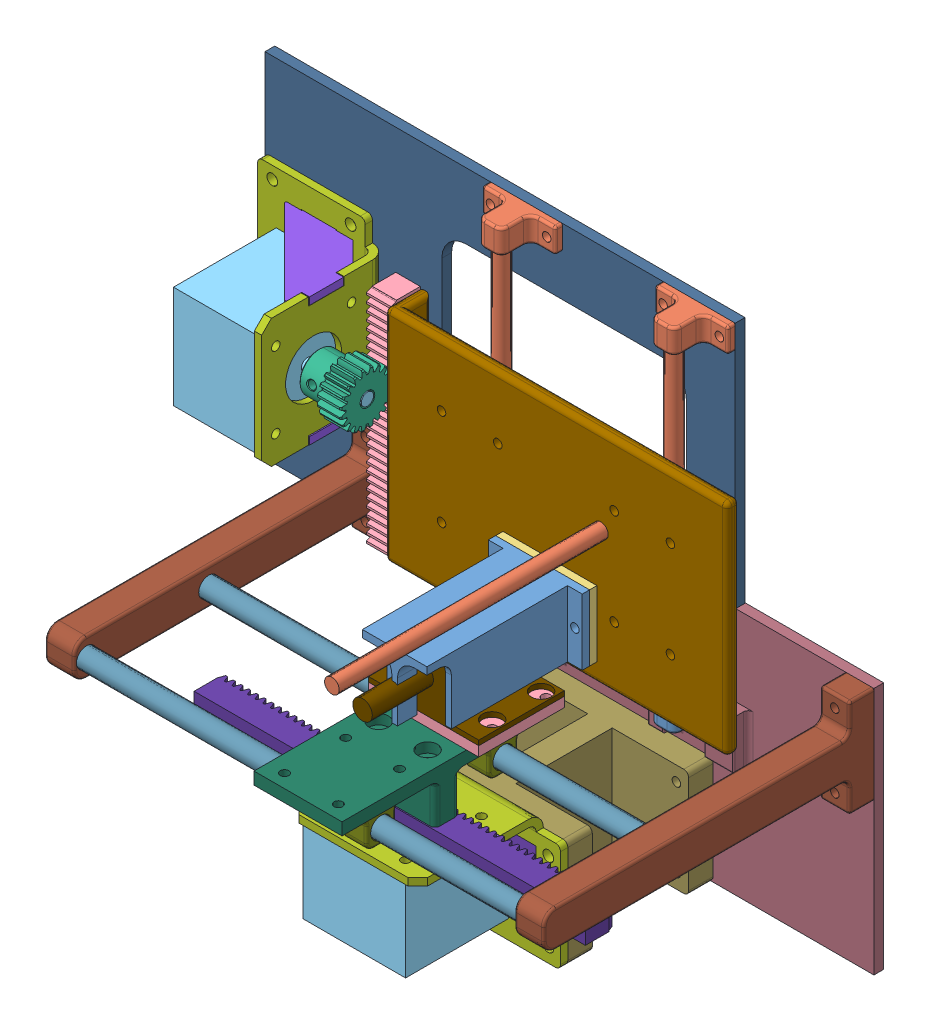
SolidWorks assembly AssemXY, configuration ﾃﾞﾌｫﾙﾄ. Lengths in mm.
Overall size (249 202.5 162.02).
43 component instances, 22 part files, 70 mates.
Components (placement in the parent):
- rinia_rail-2: rinia_rail [ﾃﾞﾌｫﾙﾄ] at (-40.4159 -125.5736 144.0481) x (1 0 0) z (0 1 0) size (30 15 144)
  - shaftholder-1: shaftholder [ﾃﾞﾌｫﾙﾄ] at (-9.9946 -2.4519 30) size (30 15 10)
  - shaft_6_4-1: shaft_6_4 [ﾃﾞﾌｫﾙﾄ] at (-9.9946 -2.4519 40) size (30 15 139)
- rinia_rail-3: rinia_rail [ﾃﾞﾌｫﾙﾄ] at (30.1841 -125.5736 144.0481) x (1 0 0) z (0 1 0) size (30 15 144)
  - shaftholder-1: shaftholder [ﾃﾞﾌｫﾙﾄ] at (-9.9946 -2.4519 30) size (30 15 10)
  - shaft_6_4-1: shaft_6_4 [ﾃﾞﾌｫﾙﾄ] at (-9.9946 -2.4519 40) size (30 15 139)
- bush_6-1: bush_6 [ﾃﾞﾌｫﾙﾄ] at (-50.4105 -14.7713 146.5) x (1 0 0) z (0 -1 0) size (30 15 10)
- bush_6-2: bush_6 [ﾃﾞﾌｫﾙﾄ] at (20.1895 -54.1713 146.5) x (1 0 0) z (0 -1 0) size (30 15 10)
- bush_6-3: bush_6 [ﾃﾞﾌｫﾙﾄ] at (-50.4105 -54.1713 146.5) x (1 0 0) z (0 -1 0) size (30 15 10)
- bush_6-4: bush_6 [ﾃﾞﾌｫﾙﾄ] at (20.1895 -14.7713 146.5) x (1 0 0) z (0 -1 0) size (30 15 10)
- RGEABL1_0Z_90_A15_B20_C20_D20-1: RGEABL1_0Z_90_A15_B20_C20_D20 [Default] at (-85.1105 5.5287 145) x (0 -1 0) z (-1 0 0) size (90 12 10)
- NEMA17-2: NEMA17 [ﾃﾞﾌｫﾙﾄ] at (-143.4105 -23.5736 166.6) x (0 1 0) z (1 0 0) size (42 42 58.3)
- SS1_20A_On-1: SS1_20A_On [Default] at (-85.1105 -23.5736 166.6) x (-1 0 0) z (0 0.98659 -0.163216) size (20 22.03 22.03)
- NEMA_17_stand_welded_from_step-1: NEMA_17_stand_welded_from_step [ﾃﾞﾌｫﾙﾄ] at (-110.1105 -23.5736 136.5) x (0 1 0) z (1 0 0) size (72.5 51.55 50.2)
  - 9241-01.02.01.02_Stojka_01-1: 9241-01.02.01.02_Stojka_01 [ﾃﾞﾌｫﾙﾄ] at (0 30.1 0) size (72.5 51.35 50)
  - 9241-01.02.01.01_Planka_01-1: 9241-01.02.01.01_Planka_01 [ﾃﾞﾌｫﾙﾄ] at (-23.25 3 0) x (0 0 -1) z (1 0 0) size (38.49 38.49 3)
  - 9241-01.02.01.01_Planka_01-2: 9241-01.02.01.01_Planka_01 [ﾃﾞﾌｫﾙﾄ] at (26.25 3 0) x (0 0 -1) z (1 0 0) size (38.49 38.49 3)
- stage-1: stage [ﾃﾞﾌｫﾙﾄ] at (-15.1105 -39.4713 159.5) x (1 0 0) z (0 1 0) size (140 14 90)
- 土台仮-1: 土台仮 [ﾃﾞﾌｫﾙﾄ] at (-60.9605 -23.5736 132.5) size (192.3 144 4)
- NEMA17-3: NEMA17 [ﾃﾞﾌｫﾙﾄ] at (-10.1105 -140.3736 226) x (1 0 0) z (0 1 0) size (42 42 58.3)
- SS1_20A_On-2: SS1_20A_On [Default] at (-10.1105 -82.0736 226) x (0 -1 0) z (-0.244476 0 0.969655) size (20 22.03 22.03)
- shaltholder_y2-1: shaltholder_y2 [ﾃﾞﾌｫﾙﾄ] at (91.8895 -72.5736 204) x (0 -1 0) z (-1 0 0) size (40 135 12.04)
- NEMA_17_stand_welded_from_step-2: NEMA_17_stand_welded_from_step [ﾃﾞﾌｫﾙﾄ] at (-10.1105 -107.0736 195.9) x (-1 0 0) z (0 1 0) size (72.5 51.55 50.2)
  - 9241-01.02.01.02_Stojka_01-1: 9241-01.02.01.02_Stojka_01 [ﾃﾞﾌｫﾙﾄ] at (0 30.1 0) size (72.5 51.35 50)
  - 9241-01.02.01.01_Planka_01-1: 9241-01.02.01.01_Planka_01 [ﾃﾞﾌｫﾙﾄ] at (-23.25 3 0) x (0 0 -1) z (1 0 0) size (38.49 38.49 3)
  - 9241-01.02.01.01_Planka_01-2: 9241-01.02.01.01_Planka_01 [ﾃﾞﾌｫﾙﾄ] at (26.25 3 0) x (0 0 -1) z (1 0 0) size (38.49 38.49 3)
- motor_base-1: motor_base [ﾃﾞﾌｫﾙﾄ] at (-10.1105 -132.0736 136.5) x (0 1 0) z (0 0 1) size (44 72.5 59.4)
- stage2-1: stage2 [ﾃﾞﾌｫﾙﾄ] at (22.7645 -103.3236 132.5) x (-1 0 0) z (0 0 1) size (138.25 101.5 10)
- shaltholder_y2-2: shaltholder_y2 [ﾃﾞﾌｫﾙﾄ] at (-112.1105 -72.5736 204) x (0 1 0) z (1 0 0) size (40 135 12.04)
- shalt_y-1: shalt_y [ﾃﾞﾌｫﾙﾄ] at (-117.1105 -45.1368 160.3442) x (0 0.898493 0.438988) z (1 0 0) size (8 8 190)
- shalt_y-3: shalt_y [ﾃﾞﾌｫﾙﾄ] at (-117.1105 -122.7501 229.2365) x (0 0.596216 -0.802824) z (1 0 0) size (8 8 190)
- stage_y-3: stage_y [ﾃﾞﾌｫﾙﾄ] at (-81.6065 -58.0784 260.4947) x (0 0 1) z (1 0 0) size (86 31.5 160)
  - stage_y-1: stage_y [ﾃﾞﾌｫﾙﾄ] at (-18.9947 2.4951 86) size (86 21.5 36)
  - bush_8-2: bush_8 [ﾃﾞﾌｫﾙﾄ] at (-44.9947 15.4951 80) x (1 0 0) z (0 0 -1) size (32 15 10)
  - bush_8-3: bush_8 [ﾃﾞﾌｫﾙﾄ] at (-44.9947 15.4951 102) x (1 0 0) z (0 0 -1) size (32 15 10)
  - bush_8-4: bush_8 [ﾃﾞﾌｫﾙﾄ] at (5.0053 15.4951 80) x (1 0 0) z (0 0 -1) size (32 15 10)
  - bush_8-5: bush_8 [ﾃﾞﾌｫﾙﾄ] at (5.0053 15.4951 102) x (1 0 0) z (0 0 -1) size (32 15 10)
  - RGEABL1_0Z_160_A70_B20-1: RGEABL1_0Z_160_A70_B20 [Default] at (-13.4947 23.9951 166) x (0 0 -1) z (0 1 0) size (160 12 10)
- solenoid-1: solenoid [ﾃﾞﾌｫﾙﾄ] at (4.8935 -56.5736 216.0962) x (1 0 0) z (0 1 0) size (45 65 27)
- solenoid_cover-1: solenoid_cover [ﾃﾞﾌｫﾙﾄ] at (5.6435 -53.5736 215.9725) x (-1 0 0) z (0 1 0) size (38.4 60.5 27)
- pen-1: pen [ﾃﾞﾌｫﾙﾄ] at (28.2756 -4.4101 184.5212) x (0.534644 0.845078 0) z (0 0 1) size (6 6 110)
- solenoid_under_cover-1: solenoid_under_cover [ﾃﾞﾌｫﾙﾄ] at (5.6435 -40.0736 182.7225) x (-1 0 0) z (0 0 1) size (38.4 27 3)
- solenoid_to_base-1: solenoid_to_base [ﾃﾞﾌｫﾙﾄ] at (4.8935 -56.5736 216.0962) x (-1 0 0) z (0 -1 0) size (45 35 4)
Mates (geometry in assembly coordinates):
- 一致2: coincident aligned: plane of rinia_rail-2/shaft_6_4-1 through (-50.4105 48.4264 146.5) normal (0 1 0); plane of rinia_rail-3/shaft_6_4-1 through (20.1895 48.4264 146.5) normal (0 1 0)
- 一致3: coincident aligned: plane of rinia_rail-2/shaft_6_4-1 through (-50.4105 48.4264 136.5) normal (0 0 -1); plane of rinia_rail-3/shaft_6_4-1 through (20.1895 48.4264 136.5) normal (0 0 -1)
- 同心円1: concentric anti-aligned: cylinder of rinia_rail-2/shaft_6_4-1 through (-50.4105 38.4264 146.5) axis (0 -1 0) radius 3; cylinder of bush_6-1 through (-50.4105 -24.7713 146.5) axis (0 1 0) radius 3.3
- 同心円2: concentric anti-aligned: cylinder of rinia_rail-2/shaft_6_4-1 through (-50.4105 38.4264 146.5) axis (0 -1 0) radius 3; cylinder of bush_6-3 through (-50.4105 -64.1713 146.5) axis (0 1 0) radius 3.3
- 同心円3: concentric anti-aligned: cylinder of rinia_rail-3/shaft_6_4-1 through (20.1895 38.4264 146.5) axis (0 -1 0) radius 3; cylinder of bush_6-4 through (20.1895 -24.7713 146.5) axis (0 1 0) radius 3.3
- 同心円4: concentric anti-aligned: cylinder of rinia_rail-3/shaft_6_4-1 through (20.1895 38.4264 146.5) axis (0 -1 0) radius 3; cylinder of bush_6-2 through (20.1895 -64.1713 146.5) axis (0 1 0) radius 3.3
- 一致4: coincident aligned: plane of bush_6-1 through (-50.4105 -24.7713 156.5) normal (0 0 1); plane of bush_6-3 through (-50.4105 -64.1713 156.5) normal (0 0 1)
- 一致5: coincident aligned: plane of bush_6-2 through (20.1895 -64.1713 156.5) normal (0 0 1); plane of bush_6-4 through (20.1895 -24.7713 156.5) normal (0 0 1)
- 一致6: coincident aligned: plane of bush_6-2 through (20.1895 -64.1713 156.5) normal (0 0 1); plane of bush_6-3 through (-50.4105 -64.1713 156.5) normal (0 0 1)
- 一致7: coincident aligned: plane of bush_6-2 through (20.1895 -64.1713 146.5) normal (0 -1 0); plane of bush_6-3 through (-50.4105 -64.1713 146.5) normal (0 -1 0)
- 一致8: coincident aligned: plane of bush_6-1 through (-50.4105 -24.7713 146.5) normal (0 -1 0); plane of bush_6-4 through (20.1895 -24.7713 146.5) normal (0 -1 0)
- 同心円5: concentric anti-aligned: cylinder of NEMA17-2 through (-85.1105 -23.5736 166.6) axis (-1 0 0) radius 2.5; cylinder of SS1_20A_On-1 through (-105.1105 -23.5736 166.6) axis (1 0 0) radius 2.5
- 一致9: coincident aligned: plane of NEMA17-2 through (-85.1105 -23.5736 166.6) normal (1 0 0); plane of SS1_20A_On-1 through (-85.1105 -21.8598 176.9592) normal (1 0 0)
- 同心円6: concentric anti-aligned: circle of NEMA17-2; circle of NEMA_17_stand_welded_from_step-1/9241-01.02.01.02_Stojka_01-1
- 一致10: coincident anti-aligned: plane of NEMA17-2 through (-110.1105 -23.5736 166.6) normal (1 0 0); plane of NEMA_17_stand_welded_from_step-1/9241-01.02.01.02_Stojka_01-1 through (-110.1105 -23.5736 166.6) normal (-1 0 0)
- 一致11: coincident aligned: plane of rinia_rail-2/shaftholder-1 through (-50.4105 -85.5736 136.5) normal (0 0 -1); plane of NEMA_17_stand_welded_from_step-1/9241-01.02.01.02_Stojka_01-1 through (-110.1105 -23.5736 136.5) normal (0 0 -1)
- 平行1: parallel anti-aligned: plane of rinia_rail-2/shaftholder-1 through (-65.4105 -85.5736 146.5) normal (-1 0 0); plane of NEMA_17_stand_welded_from_step-1/9241-01.02.01.02_Stojka_01-1 through (-107.1105 -23.5736 166.6) normal (1 0 0)
- 平行2: parallel anti-aligned: plane of NEMA17-2 through (-110.1105 -44.5736 145.6) normal (0 -1 0); plane of NEMA_17_stand_welded_from_step-1/9241-01.02.01.01_Planka_01-1 through (-110.1105 -46.8236 139.5) normal (0 1 0)
- 一致18: coincident aligned: plane of RGEABL1_0Z_90_A15_B20_C20_D20-1 through (-85.1105 5.5287 145) normal (1 0 0); plane of SS1_20A_On-1 through (-85.1105 -21.8598 176.9592) normal (1 0 0)
- 距離1: distance = 51 mm aligned: plane of rinia_rail-2/shaft_6_4-1 through (-50.4105 48.4264 146.5) normal (0 1 0); plane of NEMA17-2 through (-110.1105 -2.5736 145.6) normal (0 1 0)
- 平行5: parallel anti-aligned: plane of rinia_rail-2/shaft_6_4-1 through (-50.4105 48.4264 136.5) normal (0 0 -1); plane of bush_6-1 through (-50.4105 -24.7713 156.5) normal (0 0 1)
- 平行6: parallel aligned: plane of RGEABL1_0Z_90_A15_B20_C20_D20-1 through (-95.1105 -84.4713 145) normal (0 -1 0); plane of NEMA17-2 through (-110.1105 -44.5736 145.6) normal (0 -1 0)
- 一致25: coincident anti-aligned: circle of bush_6-3; circle of stage-1
- 同心円7: concentric aligned: circle of bush_6-1; circle of stage-1
- 同心円8: concentric anti-aligned: circle of bush_6-2; circle of stage-1
- 一致32: coincident anti-aligned: plane of RGEABL1_0Z_90_A15_B20_C20_D20-1 through (-85.1105 5.5287 145) normal (1 0 0); plane of stage-1 through (-85.1105 -84.4713 154.5) normal (-1 0 0)
- 一致33: coincident aligned: plane of RGEABL1_0Z_90_A15_B20_C20_D20-1 through (-95.1105 5.5287 157) normal (0 1 0); plane of stage-1 through (-85.1105 5.5287 154.5) normal (0 1 0)
- 一致36: coincident aligned: cylinder of RGEABL1_0Z_90_A15_B20_C20_D20-1 through (-85.1105 -69.4713 150.5) axis (-1 0 0) radius 1.75; circle of stage-1
- 一致37: coincident aligned: plane of rinia_rail-3/shaftholder-1 through (20.1895 -95.5736 146.5) normal (0 -1 0); plane of 土台仮-1 through (-60.9605 -95.5736 136.5) normal (0 -1 0)
- 一致38: coincident aligned: plane of rinia_rail-3/shaftholder-1 through (35.1895 -85.5736 146.5) normal (1 0 0); plane of 土台仮-1 through (35.1895 -23.5736 136.5) normal (1 0 0)
- 一致39: coincident anti-aligned: plane of rinia_rail-3/shaftholder-1 through (20.1895 -85.5736 136.5) normal (0 0 -1); plane of 土台仮-1 through (-60.9605 -23.5736 136.5) normal (0 0 1)
- 一致40: coincident anti-aligned: plane of 土台仮-1 through (-60.9605 -23.5736 136.5) normal (0 0 1); plane of shaltholder_y2-2 through (-100.1105 -65.0736 136.5) normal (0 0 -1)
- 距離2: distance = 5 mm anti-aligned: plane of shaltholder_y2-2 through (-100.1105 -72.5736 204) normal (1 0 0); plane of RGEABL1_0Z_90_A15_B20_C20_D20-1 through (-95.1105 5.5287 145) normal (-1 0 0)
- 同心円9: concentric anti-aligned: cylinder of NEMA17-3 through (-10.1105 -82.0736 226) axis (0 -1 0) radius 2.5; cylinder of SS1_20A_On-2 through (-10.1105 -102.0736 226) axis (0 1 0) radius 2.5
- 一致42: coincident aligned: plane of NEMA17-3 through (-10.1105 -82.0736 226) normal (0 1 0); plane of SS1_20A_On-2 through (0.0709 -82.0736 228.567) normal (0 1 0)
- 同心円10: concentric aligned: cylinder of shaltholder_y2-1 through (84.8895 -72.5736 266.5) axis (-1 0 0) radius 4.1; cylinder of shalt_y-3 through (84.8895 -72.5736 266.5) axis (-1 0 0) radius 4
- 同心円11: concentric aligned: cylinder of shaltholder_y2-1 through (84.8895 -72.5736 216.5) axis (-1 0 0) radius 4.1; cylinder of shalt_y-1 through (84.8895 -72.5736 216.5) axis (-1 0 0) radius 4
- 一致43: coincident anti-aligned: circle of shalt_y-3; plane of shaltholder_y2-1 through (84.8895 -72.5736 266.5) normal (-1 0 0)
- 一致44: coincident aligned: plane of ? through (-92.6504 -82.0736 247) normal (0 0 1); plane of NEMA17-3 through (10.8895 -107.0736 247) normal (0 0 1)
- 一致45: coincident anti-aligned: plane of ? through (-92.6504 -82.0736 247) normal (0 1 0); circle of SS1_20A_On-2
- 同心円16: concentric aligned: circle of NEMA17-3; cylinder of NEMA_17_stand_welded_from_step-2/9241-01.02.01.02_Stojka_01-1 through (-10.1105 -104.0736 226) axis (0 1 0) radius 11.5
- 一致53: coincident anti-aligned: plane of NEMA17-3 through (-10.1105 -107.0736 226) normal (0 1 0); plane of NEMA_17_stand_welded_from_step-2/9241-01.02.01.02_Stojka_01-1 through (-10.1105 -107.0736 226) normal (0 -1 0)
- 平行11: parallel aligned: plane of NEMA17-3 through (10.8895 -107.0736 247) normal (0 0 1); plane of NEMA_17_stand_welded_from_step-2/9241-01.02.01.02_Stojka_01-1 through (-36.3605 -104.0736 247.25) normal (0 0 1)
- 距離5: distance = 2 mm anti-aligned: plane of shaltholder_y2-1 through (79.8895 -80.0736 136.5) normal (0 -1 0); plane of ? through (-92.6504 -82.0736 247) normal (0 1 0)
- 距離7: distance = 69 mm anti-aligned: plane of NEMA17-3 through (10.8895 -107.0736 247) normal (1 0 0); plane of shaltholder_y2-1 through (79.8895 -72.5736 204) normal (-1 0 0)
- 一致63: coincident anti-aligned: plane of NEMA_17_stand_welded_from_step-2/9241-01.02.01.02_Stojka_01-1 through (-10.1105 -107.0736 195.9) normal (0 0 -1); plane of motor_base-1 through (-10.1105 -132.0736 195.9) normal (0 0 1)
- 一致64: coincident aligned: plane of NEMA_17_stand_welded_from_step-2/9241-01.02.01.02_Stojka_01-1 through (26.1395 -154.0736 195.9) normal (1 0 0); plane of motor_base-1 through (26.1395 -110.0736 195.9) normal (1 0 0)
- 一致65: coincident aligned: plane of NEMA_17_stand_welded_from_step-2/9241-01.02.01.02_Stojka_01-1 through (-36.3605 -154.0736 195.9) normal (0 -1 0); plane of motor_base-1 through (26.1395 -154.0736 195.9) normal (0 -1 0)
- 一致71: coincident anti-aligned: plane of motor_base-1 through (-10.1105 -132.0736 136.5) normal (0 0 -1); plane of stage2-1 through (22.7645 -103.3236 136.5) normal (0 0 1)
- 一致72: coincident aligned: plane of motor_base-1 through (26.1395 -154.0736 195.9) normal (0 -1 0); plane of stage2-1 through (91.8895 -154.0736 136.5) normal (0 -1 0)
- 一致73: coincident aligned: plane of motor_base-1 through (-46.3605 -110.0736 195.9) normal (-1 0 0); plane of stage2-1 through (-46.3605 -52.5736 136.5) normal (-1 0 0)
- 同心円29: concentric aligned: cylinder of shaltholder_y2-1 through (84.8895 -72.5736 266.5) axis (-1 0 0) radius 4.1; cylinder of shalt_y-3 through (84.8895 -72.5736 266.5) axis (-1 0 0) radius 4
- 一致78: coincident anti-aligned: plane of shaltholder_y2-1 through (79.8895 -80.0736 136.5) normal (0 0 -1); plane of stage2-1 through (22.7645 -103.3236 136.5) normal (0 0 1)
- 同心円30: concentric anti-aligned: cylinder of rinia_rail-3/shaftholder-1 through (31.6895 -90.5736 136.5) axis (0 0 1) radius 1.75; cylinder of stage2-1 through (31.6895 -90.5736 142.5) axis (0 0 -1) radius 1.75
- 一致79: coincident aligned: plane of 土台仮-1 through (-60.9605 -23.5736 132.5) normal (0 0 -1); plane of stage2-1 through (22.7645 -103.3236 132.5) normal (0 0 -1)
- 同心円31: concentric anti-aligned: cylinder of shaltholder_y2-2 through (-105.1105 -72.5736 266.5) axis (1 0 0) radius 4.1; cylinder of shalt_y-3 through (84.8895 -72.5736 266.5) axis (-1 0 0) radius 4
- 一致80: coincident anti-aligned: plane of shaltholder_y2-2 through (-105.1105 -72.5736 216.5) normal (1 0 0); plane of shalt_y-1 through (-105.1105 -72.5736 216.5) normal (-1 0 0)
- 一致81: coincident aligned: plane of shaltholder_y2-1 through (79.8895 -52.5736 146.5) normal (0 1 0); plane of stage2-1 through (91.8895 -52.5736 136.5) normal (0 1 0)
- 同心円34: concentric anti-aligned: cylinder of shalt_y-3 through (84.8895 -72.5736 266.5) axis (-1 0 0) radius 4; cylinder of stage_y-3/bush_8-5 through (10.3935 -72.5736 266.5) axis (1 0 0) radius 4.3
- 同心円35: concentric anti-aligned: cylinder of shalt_y-1 through (84.8895 -72.5736 216.5) axis (-1 0 0) radius 4; cylinder of stage_y-3/bush_8-3 through (10.3935 -72.5736 216.5) axis (1 0 0) radius 4.3
- 距離9: distance = 5 mm aligned: plane of solenoid-1 through (27.3935 -54.5736 233.5962) normal (1 0 0); plane of stage_y-3/stage_y-1 through (22.3935 -65.5736 198.5) normal (1 0 0)
- 一致85: coincident anti-aligned: plane of solenoid-1 through (-5.1065 -29.5736 233.5962) normal (-1 0 0); plane of solenoid_cover-1 through (-5.1065 -29.5736 246.2225) normal (1 0 0)
- 一致86: coincident anti-aligned: plane of solenoid-1 through (4.8935 -29.5736 216.0962) normal (0 1 0); plane of solenoid_cover-1 through (5.6435 -29.5736 215.9725) normal (0 -1 0)
- 一致93: coincident anti-aligned: plane of solenoid_cover-1 through (-7.5565 -26.5736 185.7225) normal (0 0 -1); plane of solenoid_under_cover-1 through (5.6435 -40.0736 185.7225) normal (0 0 1)
- 一致94: coincident aligned: plane of solenoid_cover-1 through (5.6435 -26.5736 215.9725) normal (0 1 0); plane of solenoid_under_cover-1 through (24.8435 -26.5736 185.7225) normal (0 1 0)
- 一致95: coincident aligned: plane of solenoid_cover-1 through (24.8435 -53.5736 188.7225) normal (1 0 0); plane of solenoid_under_cover-1 through (24.8435 -26.5736 185.7225) normal (1 0 0)
- 一致96: coincident anti-aligned: plane of solenoid-1 through (4.8935 -56.5736 216.0962) normal (0 -1 0); plane of solenoid_to_base-1 through (4.8935 -56.5736 216.0962) normal (0 1 0)
- 一致97: coincident aligned: plane of solenoid-1 through (27.3935 -54.5736 233.5962) normal (1 0 0); plane of solenoid_to_base-1 through (27.3935 -60.5736 233.5962) normal (1 0 0)
- 一致98: coincident aligned: plane of solenoid-1 through (-17.6065 -54.5736 233.5962) normal (0 0 1); plane of solenoid_to_base-1 through (-17.6065 -60.5736 233.5962) normal (0 0 1)
- 一致99: coincident anti-aligned: plane of stage_y-3/stage_y-1 through (4.3935 -60.5736 241.5) normal (0 1 0); plane of solenoid_to_base-1 through (4.8935 -60.5736 216.0962) normal (0 -1 0)
